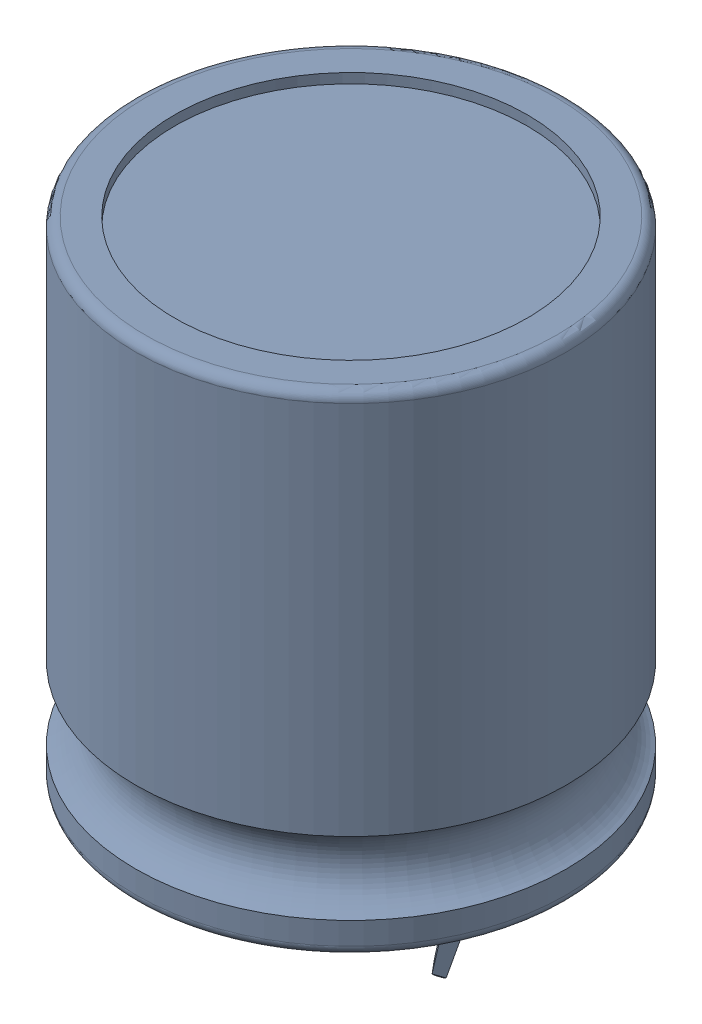
SolidWorks assembly Capacitor22x25, configuration Default. Lengths in mm.
Overall size (22 31.01 22).
3 component instances, 2 part files, 0 mates.
Components (placement in the parent):
- User_Library-ECEC2DP271BJ-1: User_Library-ECEC2DP271BJ [Default] at (8.9531 3.6858 17.317) size (22 25.01 22)
- User_Library-CAP_EL_SNAP-IN_10_35x45_Valor_predeterminado-1: User_Library-CAP_EL_SNAP-IN_10_35x45_Valor_predeterminado [Default] at (14.4607 11.8368 29.4898) x (0.642788 0 0.766044) z (-0.766044 0 0.642788) size (3.5 7.01 5.68)
- User_Library-CAP_EL_SNAP-IN_10_35x45_Valor_predeterminado-2: User_Library-CAP_EL_SNAP-IN_10_35x45_Valor_predeterminado [Default] at (2.8917 11.8368 4.8301) x (-0.67559 0 -0.737277) z (0.737277 0 -0.67559) size (3.5 7.01 5.68)
